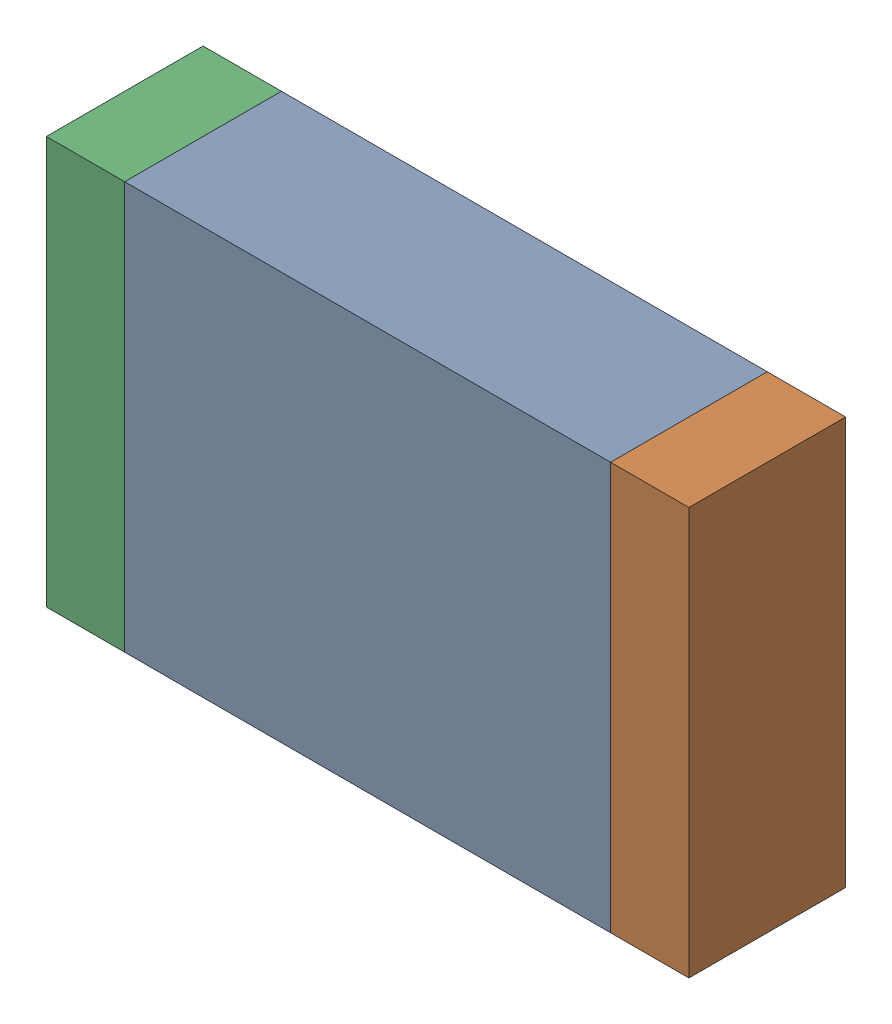
SolidWorks assembly C108, configuration Default. Lengths in mm.
Overall size (2.05 1.3 0.5).
6 component instances, 2 part files, 0 mates.
Components (placement in the parent):
- 836756464-1: 836756464 [Default] at (119.075 79.5 0) size (1.55 1.3 0.5)
  - Extruded_42-1: Extruded_42 [Default] at origin size (1.55 1.3 0.5)
- 836756336-1: 836756336 [Default] at (119.975 79.5 0) size (0.25 1.3 0.5)
  - Extruded_41-1: Extruded_41 [Default] at origin size (0.25 1.3 0.5)
- 836756336-2: 836756336 [Default] at (118.175 79.5 0) size (0.25 1.3 0.5)
  - Extruded_41-1: Extruded_41 [Default] at origin size (0.25 1.3 0.5)
